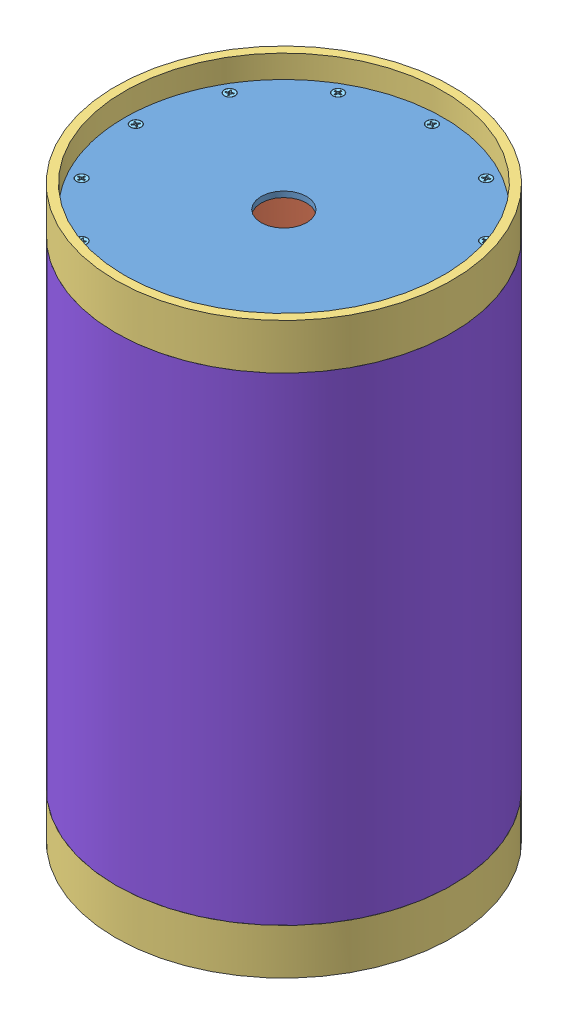
SolidWorks assembly Cryo Tank, configuration Default. Lengths in mm.
Overall size (93.73 158.75 93.73).
34 component instances, 8 part files, 29 mates.
Components (placement in the parent):
- End Cap-1: End Cap [Default] at origin size (88.9 3.17 88.9)
- Liner-1: Liner [Default] at (0 -4.7625 0) size (79.25 133.35 79.25)
- Main Ring-1: Main Ring [Default] at (0 -1.5875 0) size (93.73 25.4 93.73)
- Ring Seal-1: Ring Seal [Default] at (0 -1.5875 0) size (88.9 1.59 88.9)
- Main Ring-2: Main Ring [Default] at (0 -141.2875 0) x (-1 0 0) z (0 0 1) size (93.73 25.4 93.73)
- Ring Seal-2: Ring Seal [Default] at (0 -142.875 0) size (88.9 1.59 88.9)
- End Cap-2: End Cap [Default] at (0 -142.875 0) x (-1 0 0) z (0 0 1) size (88.9 3.17 88.9)
- 90273A015_ZINC-PLATED STL FLAT HEAD PHIL MACHINE SCREW-1: 90273A015_ZINC-PLATED STL FLAT HEAD PHIL MACHINE SCREW [90273A015] at (-35.7452 0.6985 20.6375) x (1 0 0) z (0 1 0) size (2.84 2.84 8.46)
- 90273A015_ZINC-PLATED STL FLAT HEAD PHIL MACHINE SCREW-2: 90273A015_ZINC-PLATED STL FLAT HEAD PHIL MACHINE SCREW [90273A015] at (-41.275 0.6985 0) x (0.866025 0 0.5) z (0 1 0) size (2.84 2.84 8.46)
- 90273A015_ZINC-PLATED STL FLAT HEAD PHIL MACHINE SCREW-3: 90273A015_ZINC-PLATED STL FLAT HEAD PHIL MACHINE SCREW [90273A015] at (-35.7452 0.6985 -20.6375) x (0.5 0 0.866025) z (0 1 0) size (2.84 2.84 8.46)
- 90273A015_ZINC-PLATED STL FLAT HEAD PHIL MACHINE SCREW-4: 90273A015_ZINC-PLATED STL FLAT HEAD PHIL MACHINE SCREW [90273A015] at (-20.6375 0.6985 -35.7452) x (0 0 1) z (0 1 0) size (2.84 2.84 8.46)
- 90273A015_ZINC-PLATED STL FLAT HEAD PHIL MACHINE SCREW-5: 90273A015_ZINC-PLATED STL FLAT HEAD PHIL MACHINE SCREW [90273A015] at (0 0.6985 -41.275) x (-0.5 0 0.866025) z (0 1 0) size (2.84 2.84 8.46)
- 90273A015_ZINC-PLATED STL FLAT HEAD PHIL MACHINE SCREW-6: 90273A015_ZINC-PLATED STL FLAT HEAD PHIL MACHINE SCREW [90273A015] at (20.6375 0.6985 -35.7452) x (-0.866025 0 0.5) z (0 1 0) size (2.84 2.84 8.46)
- 90273A015_ZINC-PLATED STL FLAT HEAD PHIL MACHINE SCREW-7: 90273A015_ZINC-PLATED STL FLAT HEAD PHIL MACHINE SCREW [90273A015] at (35.7452 0.6985 -20.6375) x (-1 0 0) z (0 1 0) size (2.84 2.84 8.46)
- 90273A015_ZINC-PLATED STL FLAT HEAD PHIL MACHINE SCREW-8: 90273A015_ZINC-PLATED STL FLAT HEAD PHIL MACHINE SCREW [90273A015] at (41.275 0.6985 0) x (-0.866025 0 -0.5) z (0 1 0) size (2.84 2.84 8.46)
- 90273A015_ZINC-PLATED STL FLAT HEAD PHIL MACHINE SCREW-9: 90273A015_ZINC-PLATED STL FLAT HEAD PHIL MACHINE SCREW [90273A015] at (35.7452 0.6985 20.6375) x (-0.5 0 -0.866025) z (0 1 0) size (2.84 2.84 8.46)
- 90273A015_ZINC-PLATED STL FLAT HEAD PHIL MACHINE SCREW-10: 90273A015_ZINC-PLATED STL FLAT HEAD PHIL MACHINE SCREW [90273A015] at (20.6375 0.6985 35.7452) x (0 0 -1) z (0 1 0) size (2.84 2.84 8.46)
- 90273A015_ZINC-PLATED STL FLAT HEAD PHIL MACHINE SCREW-11: 90273A015_ZINC-PLATED STL FLAT HEAD PHIL MACHINE SCREW [90273A015] at (0 0.6985 41.275) x (0.5 0 -0.866025) z (0 1 0) size (2.84 2.84 8.46)
- 90273A015_ZINC-PLATED STL FLAT HEAD PHIL MACHINE SCREW-12: 90273A015_ZINC-PLATED STL FLAT HEAD PHIL MACHINE SCREW [90273A015] at (-20.6375 0.6985 35.7452) x (0.866025 0 -0.5) z (0 1 0) size (2.84 2.84 8.46)
- 90273A015_ZINC-PLATED STL FLAT HEAD PHIL MACHINE SCREW-13: 90273A015_ZINC-PLATED STL FLAT HEAD PHIL MACHINE SCREW [90273A015] at (0 -143.5735 41.275) x (1 0 0) z (0 -1 0) size (2.84 2.84 8.46)
- 90273A015_ZINC-PLATED STL FLAT HEAD PHIL MACHINE SCREW-25: 90273A015_ZINC-PLATED STL FLAT HEAD PHIL MACHINE SCREW [90273A015] at (-20.6375 -143.5735 35.7452) x (0.866025 0 0.5) z (0 -1 0) size (2.84 2.84 8.46)
- 90273A015_ZINC-PLATED STL FLAT HEAD PHIL MACHINE SCREW-26: 90273A015_ZINC-PLATED STL FLAT HEAD PHIL MACHINE SCREW [90273A015] at (-35.7452 -143.5735 20.6375) x (0.5 0 0.866025) z (0 -1 0) size (2.84 2.84 8.46)
- 90273A015_ZINC-PLATED STL FLAT HEAD PHIL MACHINE SCREW-27: 90273A015_ZINC-PLATED STL FLAT HEAD PHIL MACHINE SCREW [90273A015] at (-41.275 -143.5735 0) x (0 0 1) z (0 -1 0) size (2.84 2.84 8.46)
- 90273A015_ZINC-PLATED STL FLAT HEAD PHIL MACHINE SCREW-28: 90273A015_ZINC-PLATED STL FLAT HEAD PHIL MACHINE SCREW [90273A015] at (-35.7452 -143.5735 -20.6375) x (-0.5 0 0.866025) z (0 -1 0) size (2.84 2.84 8.46)
- 90273A015_ZINC-PLATED STL FLAT HEAD PHIL MACHINE SCREW-29: 90273A015_ZINC-PLATED STL FLAT HEAD PHIL MACHINE SCREW [90273A015] at (-20.6375 -143.5735 -35.7452) x (-0.866025 0 0.5) z (0 -1 0) size (2.84 2.84 8.46)
- 90273A015_ZINC-PLATED STL FLAT HEAD PHIL MACHINE SCREW-30: 90273A015_ZINC-PLATED STL FLAT HEAD PHIL MACHINE SCREW [90273A015] at (0 -143.5735 -41.275) x (-1 0 0) z (0 -1 0) size (2.84 2.84 8.46)
- 90273A015_ZINC-PLATED STL FLAT HEAD PHIL MACHINE SCREW-31: 90273A015_ZINC-PLATED STL FLAT HEAD PHIL MACHINE SCREW [90273A015] at (20.6375 -143.5735 -35.7452) x (-0.866025 0 -0.5) z (0 -1 0) size (2.84 2.84 8.46)
- 90273A015_ZINC-PLATED STL FLAT HEAD PHIL MACHINE SCREW-32: 90273A015_ZINC-PLATED STL FLAT HEAD PHIL MACHINE SCREW [90273A015] at (35.7452 -143.5735 -20.6375) x (-0.5 0 -0.866025) z (0 -1 0) size (2.84 2.84 8.46)
- 90273A015_ZINC-PLATED STL FLAT HEAD PHIL MACHINE SCREW-33: 90273A015_ZINC-PLATED STL FLAT HEAD PHIL MACHINE SCREW [90273A015] at (41.275 -143.5735 0) x (0 0 -1) z (0 -1 0) size (2.84 2.84 8.46)
- 90273A015_ZINC-PLATED STL FLAT HEAD PHIL MACHINE SCREW-34: 90273A015_ZINC-PLATED STL FLAT HEAD PHIL MACHINE SCREW [90273A015] at (35.7452 -143.5735 20.6375) x (0.5 0 -0.866025) z (0 -1 0) size (2.84 2.84 8.46)
- 90273A015_ZINC-PLATED STL FLAT HEAD PHIL MACHINE SCREW-35: 90273A015_ZINC-PLATED STL FLAT HEAD PHIL MACHINE SCREW [90273A015] at (20.6375 -143.5735 35.7452) x (0.866025 0 -0.5) z (0 -1 0) size (2.84 2.84 8.46)
- CF Inner Layer-1: CF Inner Layer [Default] at (0 64.2407 0) size (80.52 133.35 80.52)
- Honeycomb Core-1: Honeycomb Core [Default] at (0 -50.3801 0) size (93.22 133.35 93.22)
- CF Outer Layer-1: CF Outer Layer [Default] at (0 15.1434 0) size (93.73 133.35 93.73)
Mates (geometry in assembly coordinates):
- Coincident13: coincident: point of Liner-1; point of assembly
- Coincident14: coincident aligned: plane of Liner-1 through (0 -4.7625 0) normal (0 0 1); plane of assembly through (0 0 0) normal (0 0 1)
- Coincident15: coincident aligned: plane of End Cap-1 through (0 0 0) normal (0 0 1); plane of assembly through (0 0 0) normal (0 0 1)
- Coincident16: coordinate: point of End Cap-1; point of assembly
- Coincident17: coincident anti-aligned: line of ? through (110 0 53.4125) axis (0 0 -1)
- Coincident18: coincident aligned: plane of Ring Seal-1 through (0 -1.5875 0) normal (0 0 1); plane of assembly through (0 0 0) normal (0 0 1)
- Coincident20: coincident anti-aligned: line of ? through (110 0 53.4125) axis (0 0 -1)
- Coincident21: coincident aligned: plane of Main Ring-1 through (0 -1.5875 0) normal (0 0 1); plane of assembly through (0 0 0) normal (0 0 1)
- Coincident22: coincident: unknown of ?
- Coincident23: coincident anti-aligned: line of Ring Seal-2 through (110 0 -87.875) axis (0 0 -1); line of assembly
- Coincident24: coincident aligned: plane of Ring Seal-2 through (0 -142.875 0) normal (0 0 1); plane of assembly through (0 0 0) normal (0 0 1)
- Coincident25: coincident: point of Ring Seal-2; point of assembly
- Coincident26: coincident aligned: line of End Cap-2 through (110 0 -197.875) axis (0 0 1); line of assembly
- Coincident27: coincident aligned: plane of End Cap-2 through (0 -142.875 0) normal (0 0 1); plane of assembly through (0 0 0) normal (0 0 1)
- Coincident28: coincident: point of End Cap-2; point of assembly
- Coincident29: coincident aligned: line of Main Ring-2 through (110 0 -196.2875) axis (0 0 1); line of assembly
- Coincident30: coincident aligned: plane of Main Ring-2 through (0 -141.2875 0) normal (0 0 1); plane of assembly through (0 0 0) normal (0 0 1)
- Coincident31: coincident: point of Main Ring-2; point of assembly
- Coincident32: coincident: unknown of ?
- Coincident33: coincident aligned: plane of End Cap-1 through (-44.45 1.5875 0) normal (0 1 0); plane of 90273A015_ZINC-PLATED STL FLAT HEAD PHIL MACHINE SCREW-1 through (-35.7452 1.5875 19.8755) normal (0 1 0)
- Concentric1: concentric anti-aligned: circle of End Cap-1; circle of 90273A015_ZINC-PLATED STL FLAT HEAD PHIL MACHINE SCREW-1
- Concentric2: concentric anti-aligned: circle of End Cap-2; circle of 90273A015_ZINC-PLATED STL FLAT HEAD PHIL MACHINE SCREW-13
- Coincident34: coincident aligned: plane of End Cap-2 through (44.45 -144.4625 0) normal (0 -1 0); plane of 90273A015_ZINC-PLATED STL FLAT HEAD PHIL MACHINE SCREW-13 through (0 -144.4625 42.037) normal (0 -1 0)
- Coincident35: coincident aligned: line of Main Ring-1 through (110 0 53.4125) axis (0 0 -1); line of CF Inner Layer-1 through (110 0 119.2407) axis (0 0 -1)
- Coincident36: coincident aligned: plane of CF Inner Layer-1 through (0 64.2407 0) normal (0 0 1); plane of assembly through (0 0 0) normal (0 0 1)
- Coincident37: coincident aligned: line of CF Inner Layer-1 through (110 0 119.2407) axis (0 0 -1); line of Honeycomb Core-1 through (110 0 4.6199) axis (0 0 -1)
- Coincident38: coincident aligned: plane of Honeycomb Core-1 through (0 -50.3801 0) normal (0 0 1); plane of assembly through (0 0 0) normal (0 0 1)
- Coincident39: coincident aligned: line of CF Inner Layer-1 through (110 0 119.2407) axis (0 0 -1); line of CF Outer Layer-1 through (110 0 70.1434) axis (0 0 -1)
- Coincident40: coincident aligned: plane of CF Outer Layer-1 through (0 15.1434 0) normal (0 0 1); plane of assembly through (0 0 0) normal (0 0 1)
